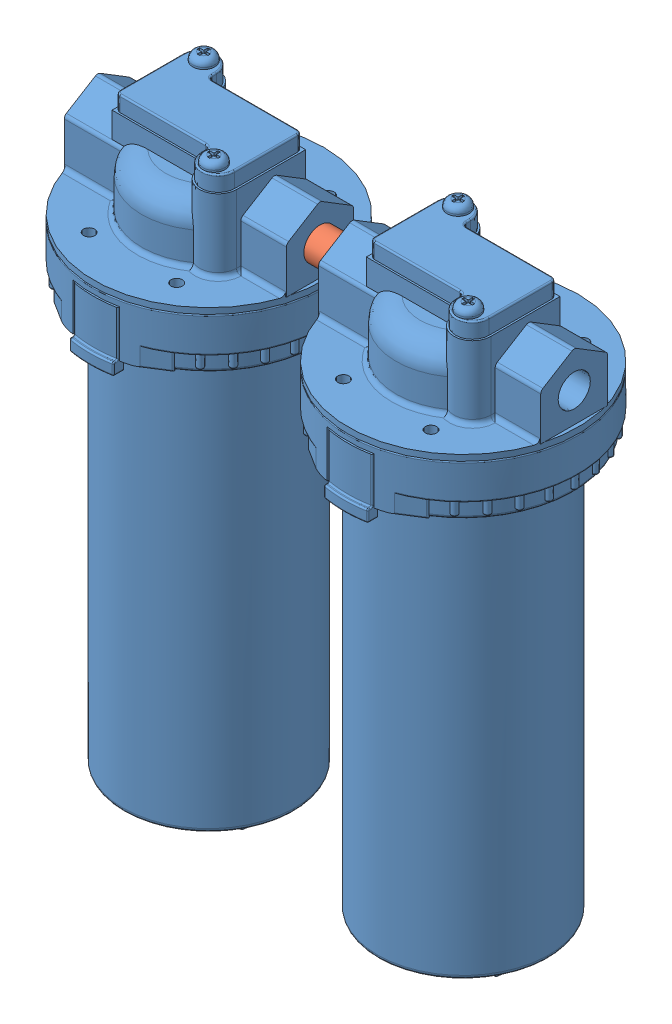
SolidWorks assembly ReadingTech_3P-060-M02-DCP, configuration Default. Lengths in mm.
Overall size (206.63 259.09 99.95).
3 component instances, 2 part files, 3 mates.
Components (placement in the parent):
- ReadingTech_3P-060-M02-P-1: ReadingTech_3P-060-M02-P [Default] at (-19.2472 -96.3506 -3.104) size (98.17 259.09 99.95)
- ReadingTech_3P-060-M02-P-2: ReadingTech_3P-060-M02-P [Default] at (89.2108 -96.3506 -3.104) size (98.17 259.09 99.95)
- ReadingTech- 60cfm_connector_.25in-1: ReadingTech- 60cfm_connector_.25in [Default] at (41.8398 119.5494 -3.104) x (0 1 0) z (0 0 1) size (13.72 13.72 13.72)
Mates (geometry in assembly coordinates):
- Coincident1: coincident anti-aligned: circle of ReadingTech_3P-060-M02-P-1; circle of ReadingTech- 60cfm_connector_.25in-1
- Coincident2: coincident aligned: circle of ReadingTech_3P-060-M02-P-2; circle of ReadingTech- 60cfm_connector_.25in-1
- Coincident3: coincident aligned: plane of ReadingTech_3P-060-M02-P-1 through (28.1238 106.8494 11.1835) normal (0 0 1); plane of ReadingTech_3P-060-M02-P-2 through (136.5818 106.8494 11.1835) normal (0 0 1)
